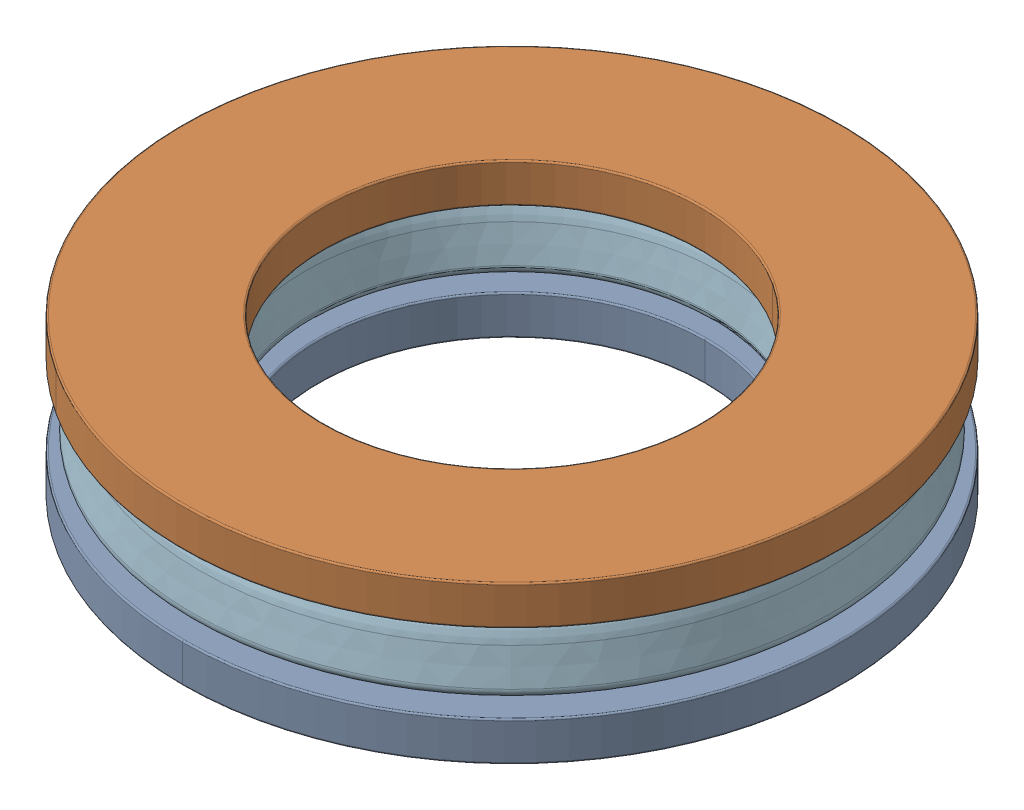
SolidWorks assembly 12mm_ID_21mm_OD_thrust_bearing, configuration Default. Lengths in mm.
Overall size (29.07 5 29.07).
14 component instances, 4 part files, 0 mates.
Components (placement in the parent):
- 1613-0521-0012 ball_1-1: 1613-0521-0012 ball_1 [Default] at (-0.0636 11.9432 -16.1059) x (0.890954 0.057695 0.450413) z (-0.453971 0.090183 0.886441) size (3 3 3)
- 1613-0521-0012 ball_1-2: 1613-0521-0012 ball_1 [Default] at (-3.0466 11.9432 -12.526) x (0.99303 0.057695 -0.102775) z (0.097342 0.090183 0.991157) size (3 3 3)
- 1613-0521-0012 ball_1-3: 1613-0521-0012 ball_1 [Default] at (-3.6206 11.9432 -7.9016) x (0.779826 0.057695 -0.623332) z (0.617749 0.090183 0.781187) size (3 3 3)
- 1613-0521-0012 ball_1-4: 1613-0521-0012 ball_1 [Default] at (-1.6033 11.9432 -3.701) x (0.319032 0.057695 -0.945986) z (0.942025 0.090183 0.323196) size (3 3 3)
- 1613-0521-0012 ball_1-5: 1613-0521-0012 ball_1 [Default] at (2.3647 11.9432 -1.2579) x (-0.243052 0.057695 -0.968296) z (0.967215 0.090183 -0.237407) size (3 3 3)
- 1613-0521-0012 ball_1-6: 1613-0521-0012 ball_1 [Default] at (7.0237 11.9432 -1.3479) x (-0.727969 0.057695 -0.683179) z (0.685321 0.090183 -0.722635) size (3 3 3)
- 1613-0521-0012 ball_1-7: 1613-0521-0012 ball_1 [Default] at (10.8945 11.9432 -3.9424) x (-0.98176 0.057695 -0.181157) z (0.185843 0.090183 -0.978432) size (3 3 3)
- 1613-0521-0012 ball_1-8: 1613-0521-0012 ball_1 [Default] at (12.748 11.9432 -8.2177) x (-0.92385 0.057695 0.378381) z (-0.37264 0.090183 -0.923584) size (3 3 3)
- 1613-0521-0012 ball_1-9: 1613-0521-0012 ball_1 [Default] at (11.9959 11.9432 -12.8165) x (-0.572624 0.057695 0.817785) z (-0.812811 0.090183 -0.575504) size (3 3 3)
- 1613-0521-0012 ball_1-10: 1613-0521-0012 ball_1 [Default] at (8.8769 11.9432 -16.2786) x (-0.039594 0.057695 0.997549) z (-0.994921 0.090183 -0.044706) size (3 3 3)
- 1613-0521-0012 ball_1-11: 1613-0521-0012 ball_1 [Default] at (4.3813 11.9432 -17.5049) x (0.506007 0.057695 0.860598) z (-0.861151 0.090183 0.500286) size (3 3 3)
- 1613-0521-0012 carriage_1-1: 1613-0521-0012 carriage_1 [Default] at (4.541 11.0282 -9.2364) x (0.704997 0 0.709211) z (-0.709211 0 0.704997) size (20.39 1.83 20.39)
- 1613-0521-0012 washer (12.3mm ID)_1-1: 1613-0521-0012 washer (12.3mm ID)_1 [Default] at (4.541 9.4432 -9.2364) size (21 1.25 21)
- 1613-0521-0012 washer (12mm ID)_1-1: 1613-0521-0012 washer (12mm ID)_1 [Default] at (4.541 14.4432 -9.2364) x (-0.837169 0 -0.546944) z (-0.546944 0 0.837169) size (21 1.25 21)
